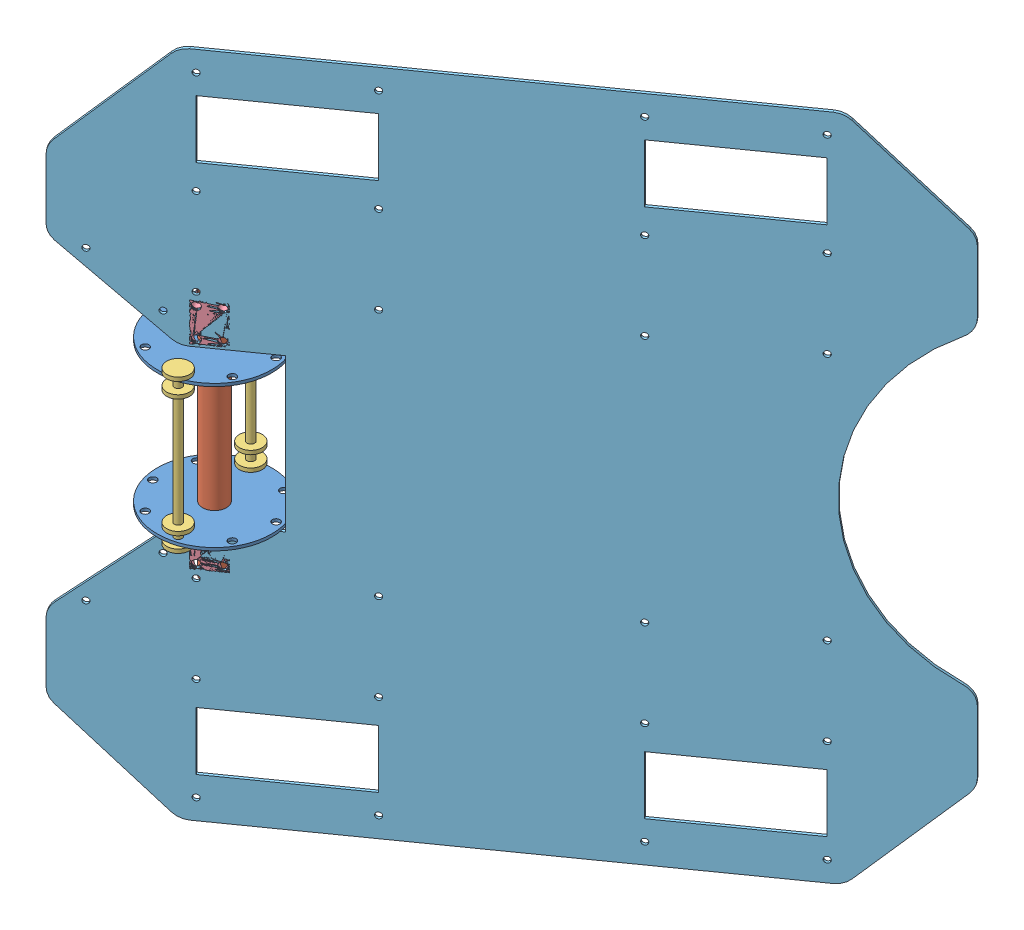
SolidWorks assembly intaker_assemble_20241126, configuration 默认. Lengths in mm.
Overall size (286.48 350 203.52).
8 component instances, 5 part files, 17 mates.
Components (placement in the parent):
- intaker_side_wall_metal_20241126-1: intaker_side_wall_metal_20241126 [默认] at (-21.3247 -6.4467 60) x (0.861429 0 0.507877) z (-0.507877 0 0.861429) size (60 1.5 60)
- intaker_side_wall_metal_20241126-2: intaker_side_wall_metal_20241126 [默认] at (-21.3247 -80.9467 60) x (-0.249999 0 -0.968246) z (0.968246 0 -0.249999) size (60 1.5 60)
- sticker_middle_plastic_20241126-1: sticker_middle_plastic_20241126 [默认] at (-21.3247 17.0533 60) x (0.991031 0 0.133629) z (0 -1 0) size (12.52 12.52 130)
- sticker_side_plastic_20241126-1: sticker_side_plastic_20241126 [默认] at (-28.6495 -38.4467 32.4679) x (0 -1 0) z (0.93678 0 -0.349918) size (80 12 12)
- sticker_side_plastic_20241126-2: sticker_side_plastic_20241126 [默认] at (-16.6304 -42.9467 86.1804) x (0 -1 0) z (-0.260937 0 -0.965356) size (80 12 12)
- chassis_intaker_connect_3d_20241126-1: chassis_intaker_connect_3d_20241126 [默认] at (-23.8273 8.1847 69.4426) x (0 -1 0) z (0.816043 0 -0.577991) size (20 17.38 15)
- chassis_intaker_connect_3d_20241126-2: chassis_intaker_connect_3d_20241126 [默认] at (-23.8273 -93.8153 69.4426) x (0 -1 0) z (0.816043 0 -0.577991) size (20 17.38 15)
- chassis_acrylic_4mm_20241126-1: chassis_acrylic_4mm_20241126 [默认] at (76.9177 -42.4467 2.1965) x (0 1 0) z (0.816043 0 -0.577991) size (350 1.5 350)
Mates (geometry in assembly coordinates):
- 同心1: concentric anti-aligned: cylinder of intaker_side_wall_metal_20241126-2 through (-21.3247 -79.4467 60) axis (0 -1 0) radius 6.2607; cylinder of sticker_middle_plastic_20241126-1 through (-21.3247 -112.9467 60) axis (0 1 0) radius 6.2607
- 同心2: concentric anti-aligned: cylinder of intaker_side_wall_metal_20241126-1 through (-21.3247 -4.9467 60) axis (0 -1 0) radius 6.2607; cylinder of sticker_middle_plastic_20241126-1 through (-21.3247 -112.9467 60) axis (0 1 0) radius 6.2607
- 同心3: concentric anti-aligned: cylinder of intaker_side_wall_metal_20241126-1 through (-14.6997 -4.9467 85.6585) axis (0 -1 0) radius 2; cylinder of sticker_side_plastic_20241126-2 through (-14.6997 -2.9467 85.6585) axis (0 1 0) radius 2
- 重合1: coincident aligned: plane of intaker_side_wall_metal_20241126-1 through (-21.3247 -4.9467 60) normal (0 1 0); circle of sticker_side_plastic_20241126-2
- 重合2: coincident anti-aligned: plane of intaker_side_wall_metal_20241126-2 through (-21.3247 -80.9467 60) normal (0 -1 0); circle of sticker_side_plastic_20241126-2
- 距离1: distance = 20 mm aligned: plane of sticker_side_plastic_20241126-2 through (-20.4919 -2.9467 87.2241) normal (0 1 0); plane of sticker_middle_plastic_20241126-1 through (-21.3247 17.0533 60) normal (0 1 0)
- 同心5: concentric anti-aligned: cylinder of intaker_side_wall_metal_20241126-2 through (-14.6997 -79.4467 85.6585) axis (0 -1 0) radius 2; cylinder of sticker_side_plastic_20241126-2 through (-14.6997 -2.9467 85.6585) axis (0 1 0) radius 2
- 同心6: concentric anti-aligned: cylinder of sticker_middle_plastic_20241126-1 through (-21.3247 -112.9467 60) axis (0 1 0) radius 6.2607; cylinder of chassis_intaker_connect_3d_20241126-1 through (-21.3247 25.0533 60) axis (0 -1 0) radius 6.2607
- 同心7: concentric anti-aligned: cylinder of sticker_middle_plastic_20241126-1 through (-21.3247 -112.9467 60) axis (0 1 0) radius 6.2607; cylinder of chassis_intaker_connect_3d_20241126-2 through (-21.3247 -76.9467 60) axis (0 -1 0) radius 6.2607
- 平行1: parallel aligned: plane of chassis_intaker_connect_3d_20241126-1 through (-8.7811 18.5533 64.7339) normal (0.577991 0 0.816043); plane of chassis_intaker_connect_3d_20241126-2 through (-8.7811 -83.4467 64.7339) normal (0.577991 0 0.816043)
- 同心8: concentric anti-aligned: cylinder of intaker_side_wall_metal_20241126-1 through (-27.9497 -4.9467 34.3415) axis (0 -1 0) radius 2; cylinder of sticker_side_plastic_20241126-1 through (-27.9497 1.5533 34.3415) axis (0 1 0) radius 2
- 重合6: coincident anti-aligned: plane of intaker_side_wall_metal_20241126-1 through (-21.3247 -6.4467 60) normal (0 -1 0); plane of sticker_side_plastic_20241126-1 through (-30.0492 -6.4467 28.7208) normal (0 1 0)
- 重合10: coincident anti-aligned: circle of chassis_intaker_connect_3d_20241126-1; circle of chassis_acrylic_4mm_20241126-1
- 重合11: coincident anti-aligned: circle of chassis_intaker_connect_3d_20241126-1; circle of chassis_acrylic_4mm_20241126-1
- 重合12: coincident anti-aligned: circle of chassis_intaker_connect_3d_20241126-2; circle of chassis_acrylic_4mm_20241126-1
- 重合13: coincident anti-aligned: circle of chassis_intaker_connect_3d_20241126-2; circle of chassis_acrylic_4mm_20241126-1
- 距离5: distance = 5 mm aligned: plane of sticker_middle_plastic_20241126-1 through (-21.3247 17.0533 60) normal (0 1 0); plane of chassis_intaker_connect_3d_20241126-1 through (-18.8221 12.0533 50.5574) normal (0 1 0)
